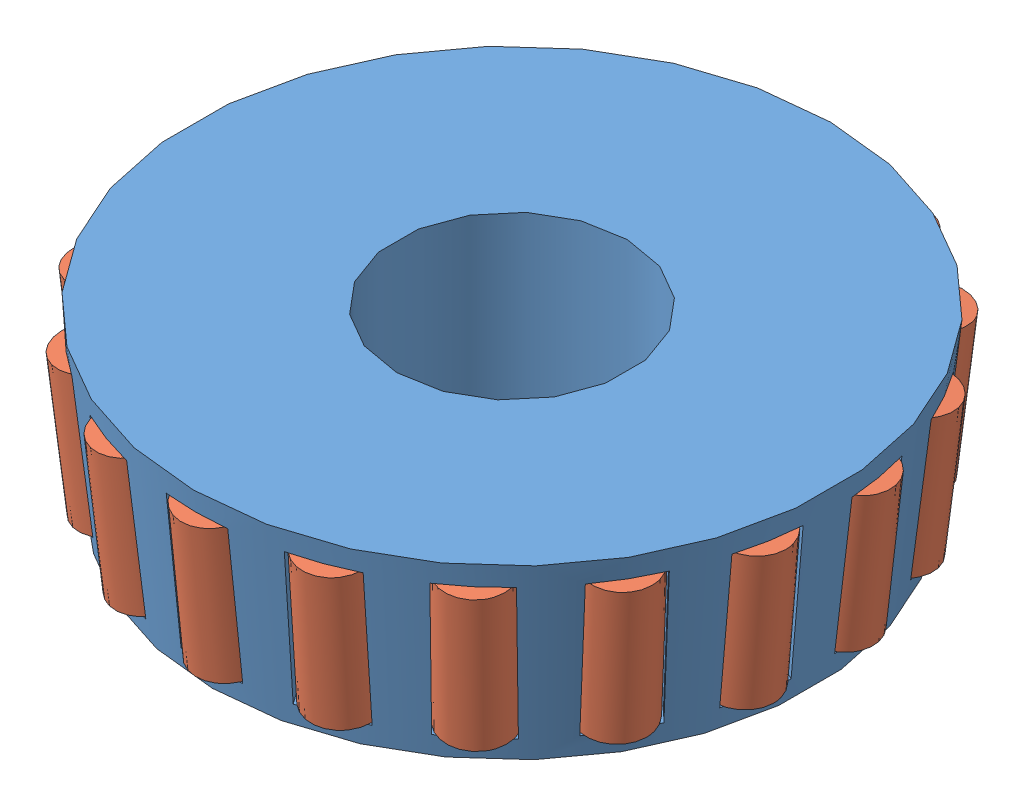
SolidWorks assembly Road Wheel Bearing Assembly, configuration Default. Lengths in mm.
Overall size (6.56 1.78 6.5).
19 component instances, 2 part files, 36 mates.
Components (placement in the parent):
- Road Wheel Bearing-1: Road Wheel Bearing [Default] at (-0.759 1.0051 -0.2823) size (6.25 1.78 6.25)
- Road Wheel Bearing Roller-1: Road Wheel Bearing Roller [Default] at (-0.759 -0.5628 2.4983) x (-0.999426 -0.00354 0.033681) z (0 0.994522 0.104528) size (0.64 0.64 1.4)
- Road Wheel Bearing Roller-2: Road Wheel Bearing Roller [Default] at (-3.2936 0.8266 -1.7456) x (0.789274 0.103648 0.60523) z (0.090524 -0.994522 0.052264) size (0.64 0.64 1.4)
- Road Wheel Bearing Roller-3: Road Wheel Bearing Roller [Default] at (-0.759 0.8266 -3.209) x (1 0 0) z (0 -0.994522 0.104528) size (0.64 0.64 1.4)
- Road Wheel Bearing Roller-4: Road Wheel Bearing Roller [Default] at (0.242 0.8266 -3.0325) x (0.927484 0.003582 0.373846) z (-0.035751 -0.994522 0.098225) size (0.64 0.64 1.4)
- Road Wheel Bearing Roller-5: Road Wheel Bearing Roller [Default] at (-2.5464 -0.5628 1.8478) x (0.99582 0.061868 0.06719) z (-0.06719 0.994522 0.080073) size (0.64 0.64 1.4)
- Road Wheel Bearing Roller-6: Road Wheel Bearing Roller [Default] at (-3.4974 -0.5628 0.2005) x (0.979533 0.098182 0.175711) z (-0.10294 0.994522 0.018151) size (0.64 0.64 1.4)
- Road Wheel Bearing Roller-7: Road Wheel Bearing Roller [Default] at (-2.6402 0.8266 -2.5243) x (0.99582 0.061868 -0.06719) z (0.06719 -0.994522 0.080073) size (0.64 0.64 1.4)
- Road Wheel Bearing Roller-8: Road Wheel Bearing Roller [Default] at (-3.1671 -0.5628 1.108) x (0.992212 0.085557 0.090524) z (-0.090524 0.994522 0.052264) size (0.64 0.64 1.4)
- Road Wheel Bearing Roller-9: Road Wheel Bearing Roller [Default] at (-1.71 -0.5628 2.3306) x (0.998836 0.032375 0.035751) z (-0.035751 0.994522 0.098225) size (0.64 0.64 1.4)
- Road Wheel Bearing Roller-10: Road Wheel Bearing Roller [Default] at (-1.76 0.8266 -3.0325) x (0.998836 0.032375 -0.035751) z (0.035751 -0.994522 0.098225) size (0.64 0.64 1.4)
- Road Wheel Bearing Roller-11: Road Wheel Bearing Roller [Default] at (-3.6412 0.8266 -0.7905) x (0.986505 0.104412 0.126122) z (0.10294 -0.994522 0.018151) size (0.64 0.64 1.4)
- Road Wheel Bearing Roller-12: Road Wheel Bearing Roller [Default] at (2.1232 0.8266 -0.7905) x (0.885883 -0.083366 0.456356) z (-0.10294 -0.994522 0.018151) size (0.64 0.64 1.4)
- Road Wheel Bearing Roller-13: Road Wheel Bearing Roller [Default] at (1.6491 -0.5628 1.108) x (0.992212 -0.085557 -0.090524) z (0.090524 0.994522 0.052264) size (0.64 0.64 1.4)
- Road Wheel Bearing Roller-14: Road Wheel Bearing Roller [Default] at (1.0284 -0.5628 1.8478) x (0.874291 -0.097355 0.47554) z (0.06719 0.994522 0.080073) size (0.64 0.64 1.4)
- Road Wheel Bearing Roller-15: Road Wheel Bearing Roller [Default] at (1.1222 0.8266 -2.5243) x (0.913673 -0.093574 -0.395532) z (-0.06719 -0.994522 0.080073) size (0.64 0.64 1.4)
- Road Wheel Bearing Roller-16: Road Wheel Bearing Roller [Default] at (1.7756 0.8266 -1.7456) x (0.899555 -0.059136 0.432785) z (-0.090524 -0.994522 0.052264) size (0.64 0.64 1.4)
- Road Wheel Bearing Roller-17: Road Wheel Bearing Roller [Default] at (1.9794 -0.5628 0.2005) x (0.989592 -0.100551 -0.10294) z (0.10294 0.994522 0.018151) size (0.64 0.64 1.4)
- Road Wheel Bearing Roller-18: Road Wheel Bearing Roller [Default] at (0.192 -0.5628 2.3306) x (0.70634 -0.094677 0.701512) z (0.035751 0.994522 0.098225) size (0.64 0.64 1.4)
Mates (geometry in assembly coordinates):
- Concentric1: concentric anti-aligned: cylinder of Road Wheel Bearing-1 through (-0.759 -0.5628 2.4983) axis (0 0.994522 0.104528) radius 0.3429; cylinder of Road Wheel Bearing Roller-1 through (-0.759 0.8266 2.6444) axis (0 -0.994522 -0.104528) radius 0.3175
- Coincident1: coincident anti-aligned: plane of Road Wheel Bearing-1 through (-0.759 -0.5628 2.4983) normal (0 0.994522 0.104528); plane of Road Wheel Bearing Roller-1 through (-0.759 -0.5628 2.4983) normal (0 -0.994522 -0.104528)
- Concentric2: concentric anti-aligned: cylinder of Road Wheel Bearing-1 through (-1.71 -0.5628 2.3306) axis (-0.035751 0.994522 0.098225) radius 0.3429; cylinder of Road Wheel Bearing Roller-9 through (-1.76 0.8266 2.4679) axis (0.035751 -0.994522 -0.098225) radius 0.3175
- Concentric3: concentric anti-aligned: cylinder of Road Wheel Bearing-1 through (-2.5464 -0.5628 1.8478) axis (-0.06719 0.994522 0.080073) radius 0.3429; cylinder of Road Wheel Bearing Roller-5 through (-2.6402 0.8266 1.9596) axis (0.06719 -0.994522 -0.080073) radius 0.3175
- Concentric4: concentric anti-aligned: cylinder of Road Wheel Bearing-1 through (-3.1671 -0.5628 1.108) axis (-0.090524 0.994522 0.052264) radius 0.3429; cylinder of Road Wheel Bearing Roller-8 through (-3.2936 0.8266 1.181) axis (0.090524 -0.994522 -0.052264) radius 0.3175
- Concentric5: concentric anti-aligned: cylinder of Road Wheel Bearing-1 through (-3.4974 -0.5628 0.2005) axis (-0.10294 0.994522 0.018151) radius 0.3429; cylinder of Road Wheel Bearing Roller-6 through (-3.6412 0.8266 0.2259) axis (0.10294 -0.994522 -0.018151) radius 0.3175
- Concentric6: concentric aligned: cylinder of Road Wheel Bearing-1 through (-3.4974 -0.5628 -0.7652) axis (-0.10294 0.994522 -0.018151) radius 0.3429; cylinder of Road Wheel Bearing Roller-11 through (-3.4974 -0.5628 -0.7652) axis (-0.10294 0.994522 -0.018151) radius 0.3175
- Concentric7: concentric aligned: cylinder of Road Wheel Bearing-1 through (-3.1671 -0.5628 -1.6726) axis (-0.090524 0.994522 -0.052264) radius 0.3429; cylinder of Road Wheel Bearing Roller-2 through (-3.1671 -0.5628 -1.6726) axis (-0.090524 0.994522 -0.052264) radius 0.3175
- Concentric8: concentric aligned: cylinder of Road Wheel Bearing-1 through (-2.5464 -0.5628 -2.4124) axis (-0.06719 0.994522 -0.080073) radius 0.3429; cylinder of Road Wheel Bearing Roller-7 through (-2.5464 -0.5628 -2.4124) axis (-0.06719 0.994522 -0.080073) radius 0.3175
- Concentric9: concentric aligned: cylinder of Road Wheel Bearing-1 through (-1.71 -0.5628 -2.8952) axis (-0.035751 0.994522 -0.098225) radius 0.3429; cylinder of Road Wheel Bearing Roller-10 through (-1.71 -0.5628 -2.8952) axis (-0.035751 0.994522 -0.098225) radius 0.3175
- Concentric10: concentric aligned: cylinder of Road Wheel Bearing-1 through (-0.759 -0.5628 -3.0629) axis (0 0.994522 -0.104528) radius 0.3429; cylinder of Road Wheel Bearing Roller-3 through (-0.759 -0.5628 -3.0629) axis (0 0.994522 -0.104528) radius 0.3175
- Concentric11: concentric aligned: cylinder of Road Wheel Bearing-1 through (0.192 -0.5628 -2.8952) axis (0.035751 0.994522 -0.098225) radius 0.3429; cylinder of Road Wheel Bearing Roller-4 through (0.192 -0.5628 -2.8952) axis (0.035751 0.994522 -0.098225) radius 0.3175
- Concentric12: concentric aligned: cylinder of Road Wheel Bearing-1 through (1.0284 -0.5628 -2.4124) axis (0.06719 0.994522 -0.080073) radius 0.3429; cylinder of Road Wheel Bearing Roller-15 through (1.0284 -0.5628 -2.4124) axis (0.06719 0.994522 -0.080073) radius 0.3175
- Concentric13: concentric aligned: cylinder of Road Wheel Bearing-1 through (1.6491 -0.5628 -1.6726) axis (0.090524 0.994522 -0.052264) radius 0.3429; cylinder of Road Wheel Bearing Roller-16 through (1.6491 -0.5628 -1.6726) axis (0.090524 0.994522 -0.052264) radius 0.3175
- Concentric14: concentric aligned: cylinder of Road Wheel Bearing-1 through (1.9794 -0.5628 -0.7652) axis (0.10294 0.994522 -0.018151) radius 0.3429; cylinder of Road Wheel Bearing Roller-12 through (1.9794 -0.5628 -0.7652) axis (0.10294 0.994522 -0.018151) radius 0.3175
- Concentric15: concentric anti-aligned: cylinder of Road Wheel Bearing-1 through (1.9794 -0.5628 0.2005) axis (0.10294 0.994522 0.018151) radius 0.3429; cylinder of Road Wheel Bearing Roller-17 through (2.1232 0.8266 0.2259) axis (-0.10294 -0.994522 -0.018151) radius 0.3175
- Concentric16: concentric anti-aligned: cylinder of Road Wheel Bearing-1 through (1.6491 -0.5628 1.108) axis (0.090524 0.994522 0.052264) radius 0.3429; cylinder of Road Wheel Bearing Roller-13 through (1.7756 0.8266 1.181) axis (-0.090524 -0.994522 -0.052264) radius 0.3175
- Concentric17: concentric anti-aligned: cylinder of Road Wheel Bearing-1 through (1.0284 -0.5628 1.8478) axis (0.06719 0.994522 0.080073) radius 0.3429; cylinder of Road Wheel Bearing Roller-14 through (1.1222 0.8266 1.9596) axis (-0.06719 -0.994522 -0.080073) radius 0.3175
- Concentric18: concentric anti-aligned: cylinder of Road Wheel Bearing-1 through (0.192 -0.5628 2.3306) axis (0.035751 0.994522 0.098225) radius 0.3429; cylinder of Road Wheel Bearing Roller-18 through (0.242 0.8266 2.4679) axis (-0.035751 -0.994522 -0.098225) radius 0.3175
- Coincident2: coincident anti-aligned: plane of Road Wheel Bearing-1 through (-1.76 0.8266 2.4679) normal (0.035751 -0.994522 -0.098225); plane of Road Wheel Bearing Roller-9 through (-1.76 0.8266 2.4679) normal (-0.035751 0.994522 0.098225)
- Coincident3: coincident anti-aligned: plane of Road Wheel Bearing-1 through (-2.6402 0.8266 1.9596) normal (0.06719 -0.994522 -0.080073); plane of Road Wheel Bearing Roller-5 through (-2.6402 0.8266 1.9596) normal (-0.06719 0.994522 0.080073)
- Coincident4: coincident anti-aligned: plane of Road Wheel Bearing-1 through (-3.2936 0.8266 1.181) normal (0.090524 -0.994522 -0.052264); plane of Road Wheel Bearing Roller-8 through (-3.2936 0.8266 1.181) normal (-0.090524 0.994522 0.052264)
- Coincident5: coincident anti-aligned: plane of Road Wheel Bearing-1 through (-3.6412 0.8266 0.2259) normal (0.10294 -0.994522 -0.018151); plane of Road Wheel Bearing Roller-6 through (-3.6412 0.8266 0.2259) normal (-0.10294 0.994522 0.018151)
- Coincident6: coincident anti-aligned: plane of Road Wheel Bearing-1 through (-3.6412 0.8266 -0.7905) normal (0.10294 -0.994522 0.018151); plane of Road Wheel Bearing Roller-11 through (-3.6412 0.8266 -0.7905) normal (-0.10294 0.994522 -0.018151)
- Coincident7: coincident anti-aligned: plane of Road Wheel Bearing-1 through (-3.2936 0.8266 -1.7456) normal (0.090524 -0.994522 0.052264); plane of Road Wheel Bearing Roller-2 through (-3.2936 0.8266 -1.7456) normal (-0.090524 0.994522 -0.052264)
- Coincident8: coincident anti-aligned: plane of Road Wheel Bearing-1 through (-2.6402 0.8266 -2.5243) normal (0.06719 -0.994522 0.080073); plane of Road Wheel Bearing Roller-7 through (-2.6402 0.8266 -2.5243) normal (-0.06719 0.994522 -0.080073)
- Coincident9: coincident anti-aligned: plane of Road Wheel Bearing-1 through (-1.76 0.8266 -3.0325) normal (0.035751 -0.994522 0.098225); plane of Road Wheel Bearing Roller-10 through (-1.76 0.8266 -3.0325) normal (-0.035751 0.994522 -0.098225)
- Coincident10: coincident anti-aligned: plane of Road Wheel Bearing-1 through (-0.759 0.8266 -3.209) normal (0 -0.994522 0.104528); plane of Road Wheel Bearing Roller-3 through (-0.759 0.8266 -3.209) normal (0 0.994522 -0.104528)
- Coincident11: coincident anti-aligned: plane of Road Wheel Bearing-1 through (0.242 0.8266 -3.0325) normal (-0.035751 -0.994522 0.098225); plane of Road Wheel Bearing Roller-4 through (0.242 0.8266 -3.0325) normal (0.035751 0.994522 -0.098225)
- Coincident12: coincident anti-aligned: plane of Road Wheel Bearing-1 through (1.1222 0.8266 -2.5243) normal (-0.06719 -0.994522 0.080073); plane of Road Wheel Bearing Roller-15 through (1.1222 0.8266 -2.5243) normal (0.06719 0.994522 -0.080073)
- Coincident13: coincident anti-aligned: plane of Road Wheel Bearing-1 through (1.7756 0.8266 -1.7456) normal (-0.090524 -0.994522 0.052264); plane of Road Wheel Bearing Roller-16 through (1.7756 0.8266 -1.7456) normal (0.090524 0.994522 -0.052264)
- Coincident14: coincident anti-aligned: plane of Road Wheel Bearing-1 through (2.1232 0.8266 -0.7905) normal (-0.10294 -0.994522 0.018151); plane of Road Wheel Bearing Roller-12 through (2.1232 0.8266 -0.7905) normal (0.10294 0.994522 -0.018151)
- Coincident15: coincident anti-aligned: plane of Road Wheel Bearing-1 through (2.1232 0.8266 0.2259) normal (-0.10294 -0.994522 -0.018151); plane of Road Wheel Bearing Roller-17 through (2.1232 0.8266 0.2259) normal (0.10294 0.994522 0.018151)
- Coincident16: coincident anti-aligned: plane of Road Wheel Bearing-1 through (1.7756 0.8266 1.181) normal (-0.090524 -0.994522 -0.052264); plane of Road Wheel Bearing Roller-13 through (1.7756 0.8266 1.181) normal (0.090524 0.994522 0.052264)
- Coincident17: coincident anti-aligned: plane of Road Wheel Bearing-1 through (1.1222 0.8266 1.9596) normal (-0.06719 -0.994522 -0.080073); plane of Road Wheel Bearing Roller-14 through (1.1222 0.8266 1.9596) normal (0.06719 0.994522 0.080073)
- Coincident18: coincident anti-aligned: plane of Road Wheel Bearing-1 through (0.242 0.8266 2.4679) normal (-0.035751 -0.994522 -0.098225); plane of Road Wheel Bearing Roller-18 through (0.242 0.8266 2.4679) normal (0.035751 0.994522 0.098225)
